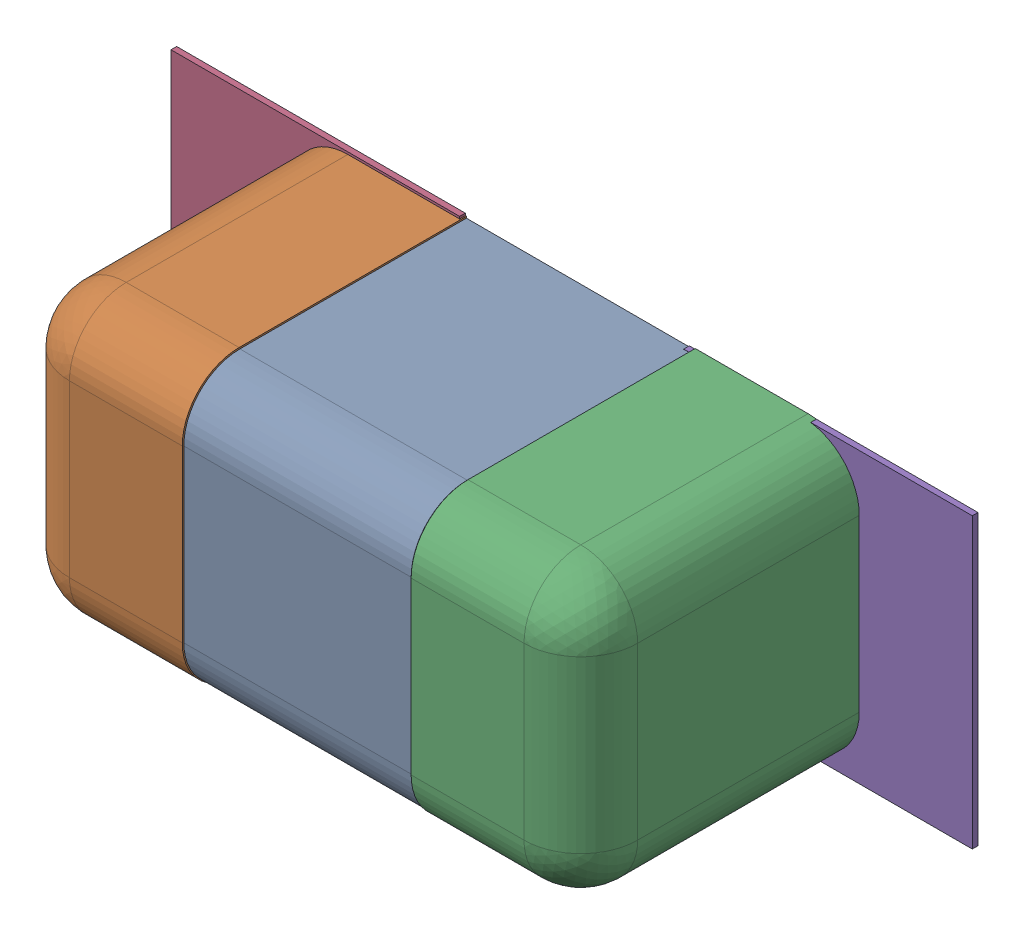
SolidWorks assembly C32, configuration Défaut. Lengths in mm.
Overall size (1.41 0.51 0.5).
8 component instances, 4 part files, 0 mates.
Components (placement in the parent):
- 6324936752-1: 6324936752 [Défaut] at (9.4742 -8.0518 0) x (1 0 0) z (0 -1 0) size (1 0.5 0.5)
  - Open CASCADE STEP translator 7.5 2.114.1.1-1: Open CASCADE STEP translator 7.5 2.114.1.1 [Défaut] at origin size (0.4 0.5 0.5)
  - Open CASCADE STEP translator 7.5 2.114.1.2-1: Open CASCADE STEP translator 7.5 2.114.1.2 [Défaut] at origin size (0.3 0.5 0.5)
  - Open CASCADE STEP translator 7.5 2.114.1.3-1: Open CASCADE STEP translator 7.5 2.114.1.3 [Défaut] at origin size (0.3 0.5 0.5)
- 6504207776-1: 6504207776 [Défaut] at (9.0169 -8.0518 0) size (0.51 0.51 0.01)
  - Extruded-1: Extruded [Défaut] at origin size (0.51 0.51 0.01)
- 6504207776-2: 6504207776 [Défaut] at (9.9192 -8.057 0) size (0.51 0.51 0.01)
  - Extruded-1: Extruded [Défaut] at origin size (0.51 0.51 0.01)
